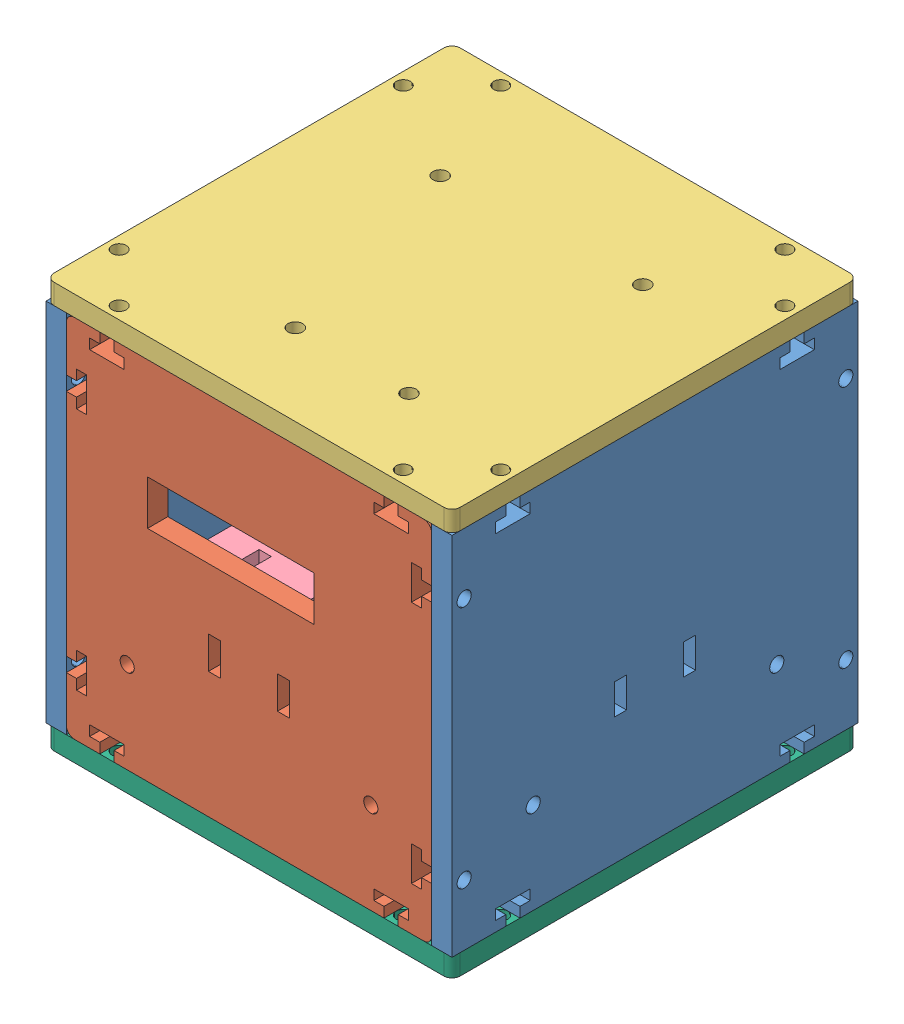
SolidWorks assembly Сборка1, configuration По умолчанию. Lengths in mm.
Overall size (100 100 100).
7 component instances, 6 part files, 10 mates.
Components (placement in the parent):
- боковина 1-1-1: боковина 1-1 [По умолчанию] at origin size (5 90 100)
- боковина 2-1-3: боковина 2-1 [По умолчанию] at (50 0 50) x (0 0 -1) z (1 0 0) size (5 90 90)
- боковина 1-1-2: боковина 1-1 [По умолчанию] at (100 0 0) x (-1 0 0) z (0 0 -1) size (5 90 100)
- днище-2: днище [По умолчанию] at (50 45 0) x (-1 0 0) z (0 1 0) size (100 100 5)
- крышка-4: крышка [По умолчанию] at (45.8401 -20.25 0) x (0 0 1) z (0 -1 0) size (89 89 5)
- боковина 2-5: боковина 2 [По умолчанию] at (50 0 -45) x (0 0 -1) z (1 0 0) size (5 90 90)
- Крышка2-1: Крышка2 [По умолчанию] at (50 -45 0) x (1 0 0) z (0 -1 0) size (100 100 5)
Mates (geometry in assembly coordinates):
- Совпадение1: coincident anti-aligned: plane of боковина 1-1-1 through (5 0 0) normal (1 0 0); plane of боковина 2-1-3 through (5 -28.25 45) normal (-1 0 0)
- Совпадение2: coincident aligned: plane of боковина 1-1-1 through (5 45 33.25) normal (0 1 0); plane of боковина 2-1-3 through (83.25 45 45) normal (0 1 0)
- Совпадение3: coincident aligned: plane of боковина 1-1-1 through (5 -45 50) normal (0 0 1); plane of боковина 2-1-3 through (7 43 50) normal (0 0 1)
- Расстояние4: distance = 75.25 mm anti-aligned: plane of крышка-4 through (7.5 -25.25 42.5) normal (0 -1 0); plane of днище-2 through (98 50 -48) normal (0 1 0)
- Совпадение17: coincident anti-aligned: plane of боковина 1-1-1 through (5 0 0) normal (1 0 0); plane of боковина 2-5 through (5 -28.25 -50) normal (-1 0 0)
- Совпадение18: coincident anti-aligned: plane of днище-2 through (98 45 -48) normal (0 -1 0); plane of боковина 2-5 through (83.25 45 -50) normal (0 1 0)
- Совпадение19: coincident aligned: plane of боковина 1-1-1 through (5 -45 -50) normal (0 0 -1); plane of боковина 2-5 through (7 43 -50) normal (0 0 -1)
- Совпадение20: coincident aligned: plane of боковина 2-5 through (7 43 -50) normal (0 0 -1); plane of Крышка2-1 through (2 -50 -50) normal (0 0 -1)
- Совпадение21: coincident aligned: plane of боковина 1-1-1 through (0 0 0) normal (-1 0 0); plane of Крышка2-1 through (0 -50 -48) normal (-1 0 0)
- Совпадение22: coincident anti-aligned: plane of боковина 2-5 through (83.25 -45 -50) normal (0 -1 0); plane of Крышка2-1 through (2 -45 -48) normal (0 1 0)
